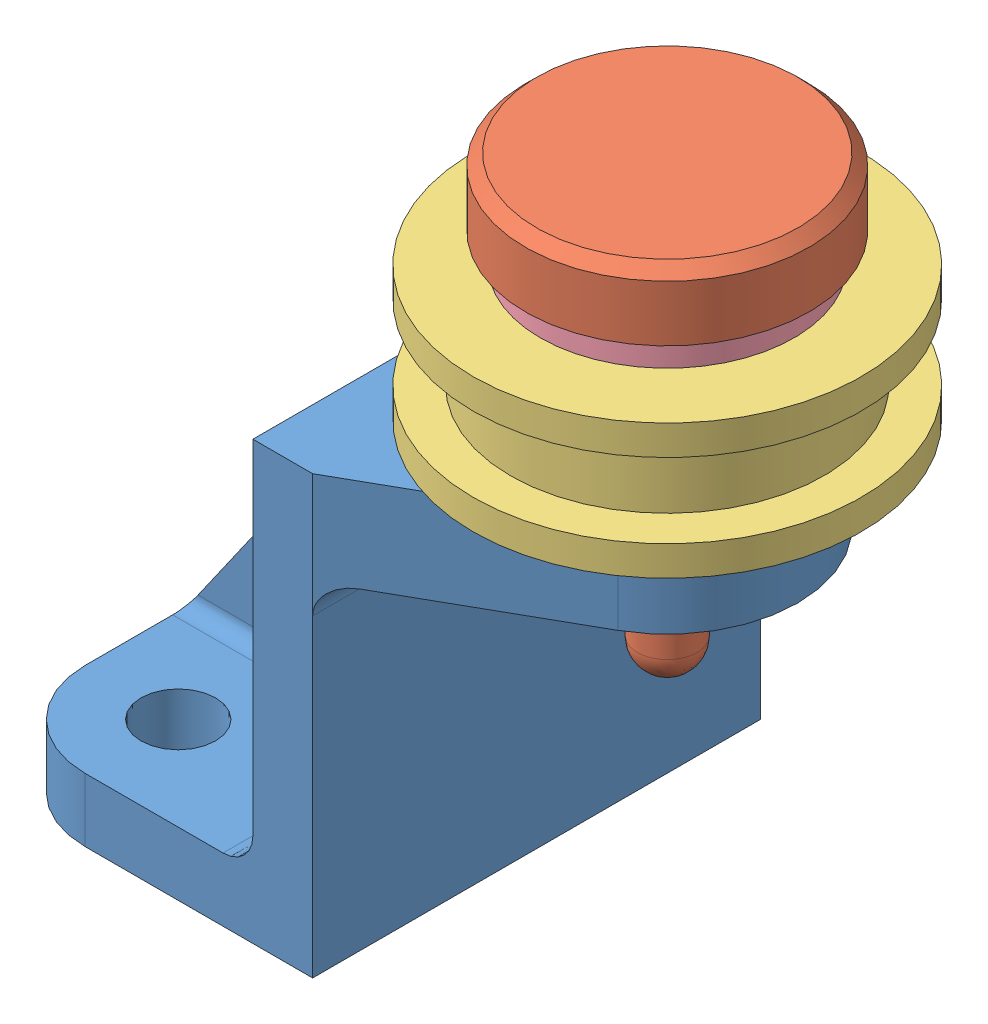
SolidWorks assembly Assem1, configuration Default. Lengths in mm.
Overall size (173.22 179 120).
4 component instances, 4 part files, 6 mates.
Components (placement in the parent):
- Part1-1: Part1 [Default] at (4.08 2.5592 150.2705) size (156 117 120)
- Part2-1: Part2 [Default] at (69.58 163.5592 150.2705) x (-0.854294 0 -0.519791) z (0.519791 0 -0.854294) size (76 120 76)
- Part3-1: Part3 [Default] at (69.58 137.5592 150.2705) size (104 36 104)
- Part4-1: Part4 [Default] at (69.58 163.5592 150.2705) size (68 44 68)
Mates (geometry in assembly coordinates):
- Concentric1: concentric aligned: cylinder of Part3-1 through (69.58 181.9538 150.2705) axis (0 1 0) radius 25; cylinder of Part4-1 through (69.58 187.7171 150.2705) axis (0 1 0) radius 25
- Coincident1: coincident anti-aligned: plane of Part3-1 through (69.58 155.5592 150.2705) normal (0 1 0); plane of Part4-1 through (69.58 155.5592 150.2705) normal (0 -1 0)
- Concentric2: concentric aligned: cylinder of Part2-1 through (69.58 231.2771 150.2705) axis (0 1 0) radius 17.5; cylinder of Part4-1 through (69.58 187.7171 150.2705) axis (0 1 0) radius 17.5
- Coincident2: coincident anti-aligned: plane of Part2-1 through (69.58 163.5592 150.2705) normal (0 -1 0); plane of Part4-1 through (69.58 163.5592 150.2705) normal (0 1 0)
- Concentric3: concentric aligned: cylinder of Part1-1 through (69.58 94.5592 150.2705) axis (0 1 0) radius 8.5; cylinder of Part2-1 through (69.58 231.2771 150.2705) axis (0 1 0) radius 8
- Coincident3: coincident anti-aligned: plane of Part1-1 through (4.08 119.5592 150.2705) normal (0 1 0); plane of Part3-1 through (69.58 119.5592 150.2705) normal (0 -1 0)
